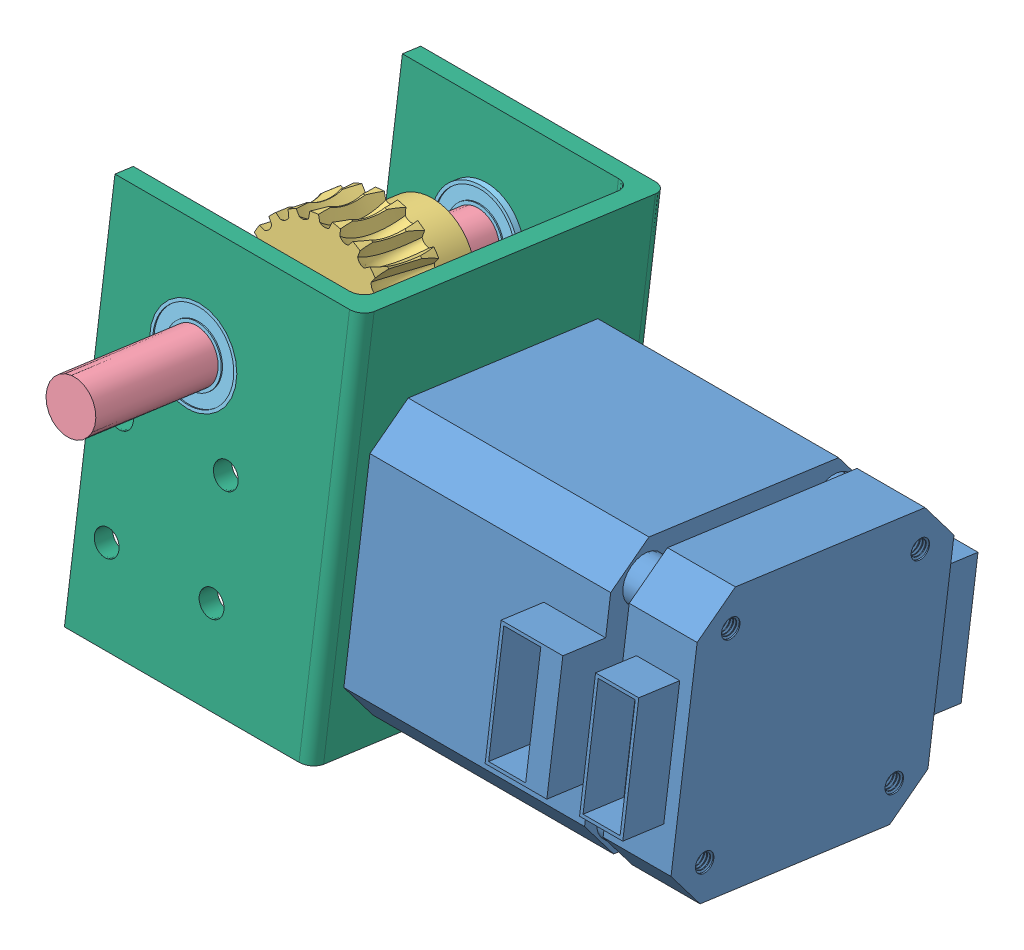
SolidWorks assembly Asm_42Driver_90Degree_Shoulder, configuration 默认. Lengths in mm.
Overall size (100.8 66.26 73.14).
7 component instances, 6 part files, 14 mates.
Components (placement in the parent):
- Part_42Motor-1: Part_42Motor [默认] at (65.4672 -14.0309 56.4881) x (0 0.990656 -0.136383) z (0 0.136383 0.990656) size (42 76 55.7)
- Part_Shaft_1Modulus_1Teeth_42SMotor-1: Part_Shaft_1Modulus_1Teeth_42SMotor [默认] at (-21.5328 3.9089 32.8203) x (1 0 0) z (0 -0.868578 0.495552) size (33.1 17.69 17.84)
- Part_Turbine_1Modulus_20Teeth_42SMotor-1: Part_Turbine_1Modulus_20Teeth_42SMotor [默认] at (-12.5328 22.4226 35.3187) x (0 -0.990656 0.136383) z (1 0 0) size (29.84 18 44.58)
- Part_Axis_8mm_Turbine_Rocker-1: Part_Axis_8mm_Turbine_Rocker [默认] at (-12.5328 18.3311 5.599) x (0.931599 0.360092 -0.049574) z (0 0.136383 0.990656) size (8 17.7 70)
- Part_Bearing_MR148ZZ-1: Part_Bearing_MR148ZZ [默认] at (-12.5328 18.8767 9.5616) x (0 -0.136383 -0.990656) z (0.425184 0.89665 -0.123441) size (4 14 14)
- Part_Bearing_MR148ZZ-2: Part_Bearing_MR148ZZ [默认] at (-12.5328 25.1503 55.1318) x (0 -0.136383 -0.990656) z (-0.945462 0.322689 -0.044424) size (4 14 14)
- Part_Flange_42Motor_Shoulder-1: Part_Flange_42Motor_Shoulder [默认] at (-27.5328 -24.2671 11.4634) x (0 0.990656 -0.136383) z (0 -0.136383 -0.990656) size (60 40 50)
Mates (geometry in assembly coordinates):
- 重合8: coincident aligned: line of Part_Shaft_1Modulus_1Teeth_42SMotor-1 through (-21.5328 3.9089 32.8203) axis (1 0 0); line of Part_Turbine_1Modulus_20Teeth_42SMotor-1 through (-31.181 3.9089 32.8203) axis (1 0 0)
- 同心5: concentric anti-aligned: cylinder of Part_Shaft_1Modulus_1Teeth_42SMotor-1 through (8.4672 3.9089 32.8203) axis (-1 0 0) radius 2.5; cylinder of Part_42Motor-1 through (-10.5328 3.9089 32.8203) axis (1 0 0) radius 2.5
- 距离7: distance = 4 mm anti-aligned: plane of Part_Shaft_1Modulus_1Teeth_42SMotor-1 through (8.4672 3.9089 32.8203) normal (1 0 0); plane of Part_42Motor-1 through (4.4672 -14.0309 56.4881) normal (-1 0 0)
- 平行6: parallel aligned: plane of Part_42Motor-1 through (12.4672 -14.3103 14.1304) normal (0 -0.136383 -0.990656); plane of Part_Turbine_1Modulus_20Teeth_42SMotor-1 through (-12.5328 21.0588 25.4121) normal (0 -0.136383 -0.990656)
- 同心6: concentric anti-aligned: cylinder of Part_Turbine_1Modulus_20Teeth_42SMotor-1 through (-12.5328 21.0588 25.4121) axis (0 0.136383 0.990656) radius 4; cylinder of Part_Axis_8mm_Turbine_Rocker-1 through (-12.5328 27.8779 74.9449) axis (0 -0.136383 -0.990656) radius 4
- 同心7: concentric anti-aligned: cylinder of Part_Axis_8mm_Turbine_Rocker-1 through (-12.5328 27.8779 74.9449) axis (0 -0.136383 -0.990656) radius 4; cylinder of Part_Bearing_MR148ZZ-2 through (-12.5328 24.6047 51.1692) axis (0 0.136383 0.990656) radius 4
- 同心8: concentric anti-aligned: cylinder of Part_Axis_8mm_Turbine_Rocker-1 through (-12.5328 27.8779 74.9449) axis (0 -0.136383 -0.990656) radius 4; cylinder of Part_Bearing_MR148ZZ-1 through (-12.5328 18.3311 5.599) axis (0 0.136383 0.990656) radius 4
- 重合13: coincident: plane of Part_Axis_8mm_Turbine_Rocker-1 through (-12.5328 18.3311 5.599) normal (0 -0.136383 -0.990656); plane of Part_Bearing_MR148ZZ-1 through (-12.5328 18.3311 5.599) normal (0 -0.136383 -0.990656)
- 重合14: coincident anti-aligned: plane of Part_42Motor-1 through (12.4672 -14.0309 56.4881) normal (-1 0 0); plane of Part_Flange_42Motor_Shoulder-1 through (12.4672 41.7187 50.832) normal (1 0 0)
- 同心10: concentric anti-aligned: circle of Part_42Motor-1; cylinder of Part_Flange_42Motor_Shoulder-1 through (-27.5338 -13.5602 19.579) axis (1 0 0) radius 2.5
- 同心11: concentric anti-aligned: circle of Part_42Motor-1; cylinder of Part_Flange_42Motor_Shoulder-1 through (-27.5338 17.1501 15.3512) axis (1 0 0) radius 2.5
- 同心12: concentric anti-aligned: cylinder of Part_Bearing_MR148ZZ-1 through (-12.5328 18.3311 5.599) axis (0 0.136383 0.990656) radius 7; cylinder of Part_Flange_42Motor_Shoulder-1 through (-12.5328 25.1503 55.1318) axis (0 -0.136383 -0.990656) radius 7
- 重合15: coincident aligned: plane of Part_Bearing_MR148ZZ-1 through (-12.5328 18.3311 5.599) normal (0 -0.136383 -0.990656); plane of Part_Flange_42Motor_Shoulder-1 through (10.4672 35.1723 3.2805) normal (0 -0.136383 -0.990656)
- 重合16: coincident aligned: plane of Part_Bearing_MR148ZZ-2 through (-12.5328 25.1503 55.1318) normal (0 0.136383 0.990656); plane of Part_Flange_42Motor_Shoulder-1 through (-27.5328 41.9914 52.8133) normal (0 0.136383 0.990656)
